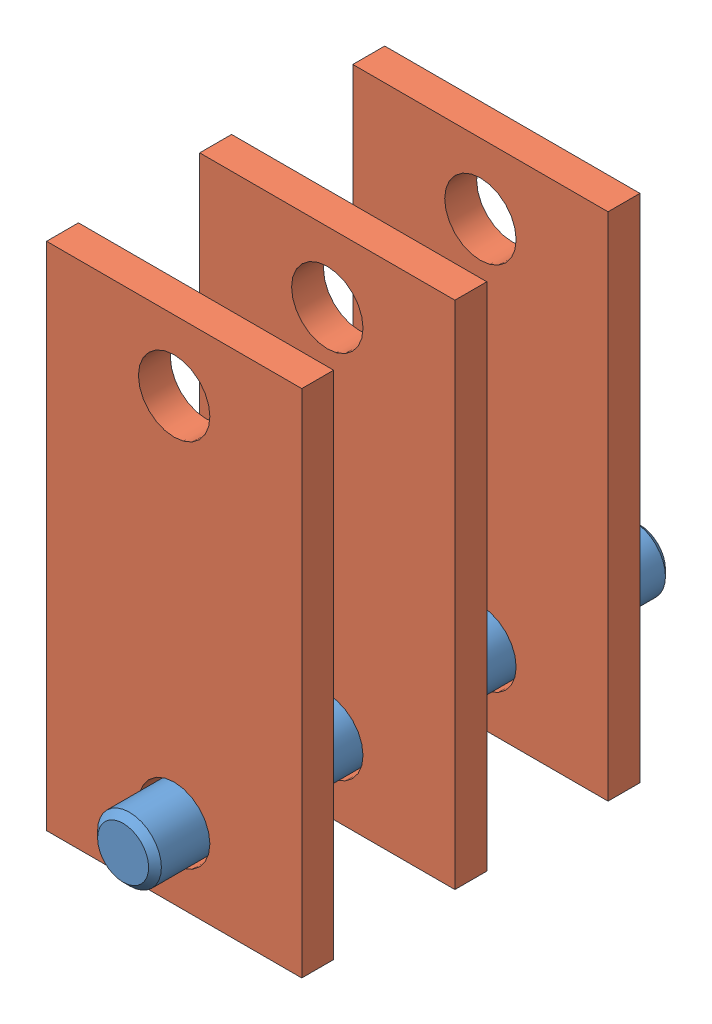
SolidWorks assembly Hammer Subassembly, configuration Default. Lengths in mm.
Overall size (50.8 101.6 102.87).
4 component instances, 2 part files, 9 mates.
Components (placement in the parent):
- Shaft Assembly - Small Hammer Shaft-1: Shaft Assembly - Small Hammer Shaft [1346K11] at (116.1994 158.8147 232.8476) size (12.7 12.7 102.87)
- Hammer-2: Hammer [Default] at (141.5994 144.8447 213.1626) x (-1 0 0) z (0 -1 0) size (50.8 6.35 101.6)
- Hammer-4: Hammer [Default] at (141.5994 144.8447 274.1226) x (-1 0 0) z (0 -1 0) size (50.8 6.35 101.6)
- Hammer-5: Hammer [Default] at (141.5994 144.8447 243.6426) x (-1 0 0) z (0 -1 0) size (50.8 6.35 101.6)
Mates (geometry in assembly coordinates):
- Concentric2: concentric anti-aligned: cylinder of Shaft Assembly - Small Hammer Shaft-1 through (116.1994 158.8147 284.2826) axis (0 0 -1) radius 6.35; cylinder of Shaft Assembly - Hammer-2 through (116.1994 158.8147 206.8126) axis (0 0 1) radius 7.112
- Coincident7: coincident: line of Shaft Assembly - Small Hammer Shaft-1 through (116.1994 165.1647 206.8126) axis (0 -1 0); plane of Shaft Assembly - Hammer-2 through (141.5994 144.8447 206.8126) normal (0 0 -1)
- Parallel3: parallel aligned: line of Shaft Assembly - Small Hammer Shaft-1 through (116.1994 165.1647 206.8126) axis (0 -1 0); line of Shaft Assembly - Hammer-2 through (141.5994 246.4447 206.8126) axis (0 -1 0)
- Concentric4: concentric anti-aligned: cylinder of Shaft Assembly - Small Hammer Shaft-1 through (116.1994 158.8147 284.2826) axis (0 0 -1) radius 6.35; cylinder of Shaft Assembly - Hammer-5 through (116.1994 158.8147 237.2926) axis (0 0 1) radius 7.112
- Parallel6: parallel anti-aligned: line of Shaft Assembly - Small Hammer Shaft-1 through (116.1994 165.1647 237.2926) axis (0 -1 0); line of Shaft Assembly - Hammer-5 through (90.7994 144.8447 237.2926) axis (0 1 0)
- Coincident13: coincident: line of Shaft Assembly - Small Hammer Shaft-1 through (116.1994 165.1647 237.2926) axis (0 -1 0); plane of Shaft Assembly - Hammer-5 through (141.5994 144.8447 237.2926) normal (0 0 -1)
- Concentric6: concentric anti-aligned: cylinder of Shaft Assembly - Small Hammer Shaft-1 through (116.1994 158.8147 284.2826) axis (0 0 -1) radius 6.35; cylinder of Shaft Assembly - Hammer-4 through (116.1994 158.8147 267.7726) axis (0 0 1) radius 7.112
- Coincident16: coincident: line of Shaft Assembly - Small Hammer Shaft-1 through (116.1994 165.1647 267.7726) axis (0 -1 0); plane of Shaft Assembly - Hammer-4 through (141.5994 144.8447 267.7726) normal (0 0 -1)
- Parallel8: parallel anti-aligned: line of Shaft Assembly - Small Hammer Shaft-1 through (116.1994 165.1647 267.7726) axis (0 -1 0); line of Shaft Assembly - Hammer-4 through (90.7994 144.8447 267.7726) axis (0 1 0)
